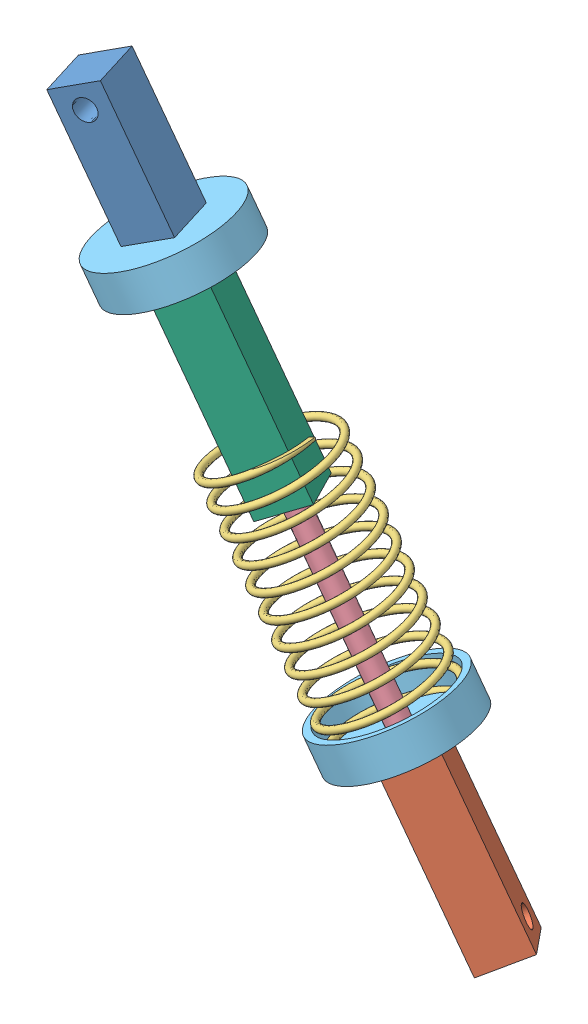
SolidWorks assembly suspension front right, configuration Default. Lengths in mm.
Overall size (55.02 99.13 33.05).
7 component instances, 6 part files, 12 mates.
Components (placement in the parent):
- ball joint-1: ball joint [Default] at (-36.9903 75.813 11.3866) x (-0.850545 -0.454684 0.264265) z (-0.296192 -0.001062 -0.955128) size (7 19 7)
- ball joint down-2: ball joint down [Default] at (-9.9949 20.485 3.0767) x (0.641575 0.201888 0.740015) z (0.632089 0.407406 -0.659154) size (7 26 7)
- Spring front-1: Spring front [Default] at (-9.9949 20.485 3.0767) x (0.898815 0.438326 0.001458) z (0.057337 -0.120868 0.991011) size (17.22 38.53 19.28)
- suspension shaft-1: suspension shaft [Default] at (-29.5502 60.5643 9.0964) x (0.065731 0.179495 -0.98156) z (-0.89824 -0.417756 -0.136545) size (3 65 3)
- washer-1: washer [Default] at (-9.9949 20.485 3.0767) x (-0.648449 -0.206332 -0.732762) z (0.625035 0.405174 -0.667207) size (19 5 19)
- washer-2: washer [Default] at (-36.9903 75.813 11.3866) x (0.163865 0.224237 -0.960659) z (-0.885609 -0.395546 -0.243392) size (19 5 19)
- suspension shaft 1-1: suspension shaft 1 [Default] at (-40.9013 83.8288 12.5906) x (-0.752998 -0.44078 0.488577) z (0.494115 0.111588 0.862206) size (7 42 7)
Mates (geometry in assembly coordinates):
- Concentric4: concentric aligned: cylinder of suspension shaft-1 through (-1.3037 2.672 0.4013) axis (-0.434562 0.890652 0.13377) radius 1.5; cylinder of washer-2 through (-36.5557 74.9223 11.2529) axis (-0.434562 0.890652 0.13377) radius 2.5
- Coincident4: coincident: point of ball joint down-2
- Coincident8: coincident aligned: plane of Spring front-1 through (-9.9949 20.485 3.0767) normal (0.434562 -0.890652 -0.13377); plane of washer-1 through (-9.9949 20.485 3.0767) normal (0.434562 -0.890652 -0.13377)
- Concentric7: concentric aligned: line of Spring front-1 through (-9.9949 20.485 3.0767) axis (-0.434562 0.890652 0.13377); cylinder of suspension shaft-1 through (-1.3037 2.672 0.4013) axis (-0.434562 0.890652 0.13377) radius 1.5
- Concentric8: concentric anti-aligned: cylinder of suspension shaft-1 through (-1.3037 2.672 0.4013) axis (-0.434562 0.890652 0.13377) radius 1.5; cylinder of washer-1 through (-10.4295 21.3757 3.2105) axis (0.434562 -0.890652 -0.13377) radius 2.5
- Coincident9: coincident anti-aligned: plane of ball joint-1 through (-36.9903 75.813 11.3866) normal (0.434562 -0.890652 -0.13377); plane of washer-2 through (-36.9903 75.813 11.3866) normal (-0.434562 0.890652 0.13377)
- Concentric9: concentric anti-aligned: cylinder of ball joint-1 through (-42.6396 87.3914 13.1257) axis (0.434562 -0.890652 -0.13377) radius 2; cylinder of washer-2 through (-36.5557 74.9223 11.2529) axis (-0.434562 0.890652 0.13377) radius 2.5
- Concentric10: concentric aligned: cylinder of washer-2 through (-36.5557 74.9223 11.2529) axis (-0.434562 0.890652 0.13377) radius 2.5; cylinder of suspension shaft 1-1 through (-36.5557 74.9223 11.2529) axis (-0.434562 0.890652 0.13377) radius 2
- Coincident10: coincident anti-aligned: plane of washer-2 through (-36.5557 74.9223 11.2529) normal (0.434562 -0.890652 -0.13377); plane of suspension shaft 1-1 through (-36.5557 74.9223 11.2529) normal (-0.434562 0.890652 0.13377)
- Concentric11: concentric aligned: cylinder of suspension shaft-1 through (-1.3037 2.672 0.4013) axis (-0.434562 0.890652 0.13377) radius 1.5; cylinder of suspension shaft 1-1 through (-22.6497 46.4214 6.9722) axis (-0.434562 0.890652 0.13377) radius 2
- Coincident11: coincident anti-aligned: plane of ball joint down-2 through (4.4907 7.1474 -10.5729) normal (-0.434562 0.890652 0.13377); plane of suspension shaft-1 through (-1.3037 2.672 0.4013) normal (0.434562 -0.890652 -0.13377)
- Concentric12: concentric aligned: cylinder of ball joint down-2 through (-1.3037 2.672 0.4013) axis (-0.434562 0.890652 0.13377) radius 2; cylinder of suspension shaft-1 through (-1.3037 2.672 0.4013) axis (-0.434562 0.890652 0.13377) radius 1.5
